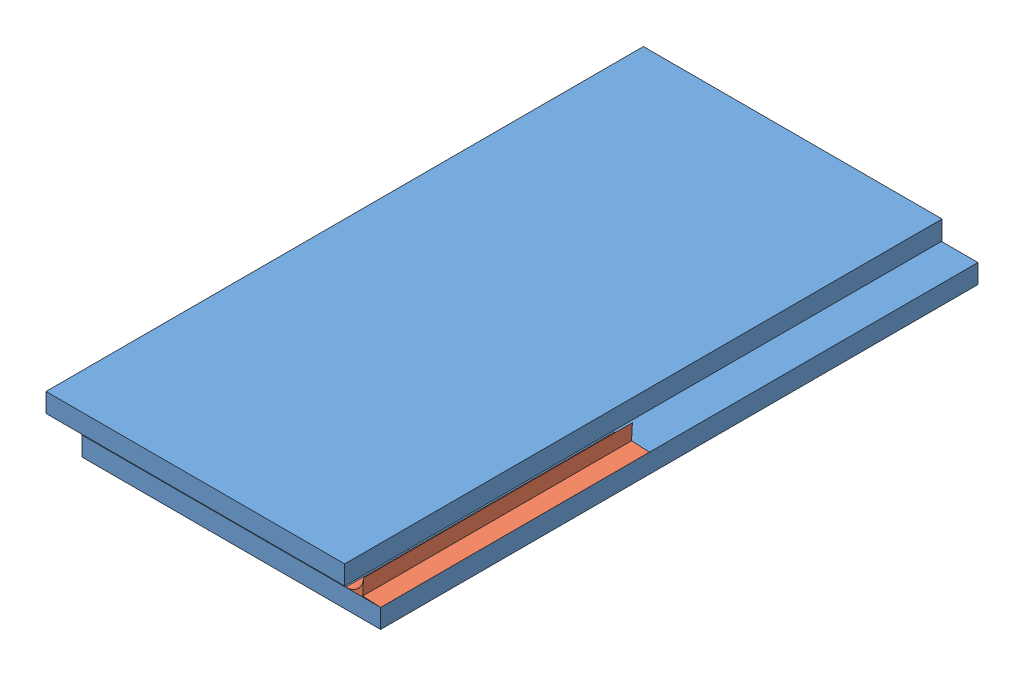
SolidWorks assembly moule_bas, configuration Default. Lengths in mm.
Overall size (280.78 32.5 500.02).
3 component instances, 2 part files, 3 mates.
Components (placement in the parent):
- Part3^moule_bas-1: Part3^moule_bas [Default] at origin size (250 16 500) (virtual)
- coin_negatif_fill_moule-1: coin_negatif_fill_moule [Default] at (235.0206 16.785 275) x (0.99863 -0.052336 0) z (0 0 1) size (29.27 15.03 225)
- Part3^moule_bas-2: Part3^moule_bas [Default] at (-30.0699 16.5 -0.0214) size (250 16 500) (virtual)
Mates (geometry in assembly coordinates):
- Coincident1: coincident anti-aligned: line of Part3^moule_bas-1 through (250 16 500) axis (-1 0 0); line of coin_negatif_fill_moule-1 through (220.6933 16 500) axis (1 0 0)
- Coincident2: coincident aligned: line of Part3^moule_bas-1 through (250 16 500) axis (0 0 -1); line of coin_negatif_fill_moule-1 through (250 16 500) axis (0 0 -1)
- Distance1: distance = 0.5 mm anti-aligned: plane of Part3^moule_bas-2 through (-30.0699 16.5 499.9786) normal (0 -1 0); plane of Part3^moule_bas-1 through (0 16 500) normal (0 1 0)
